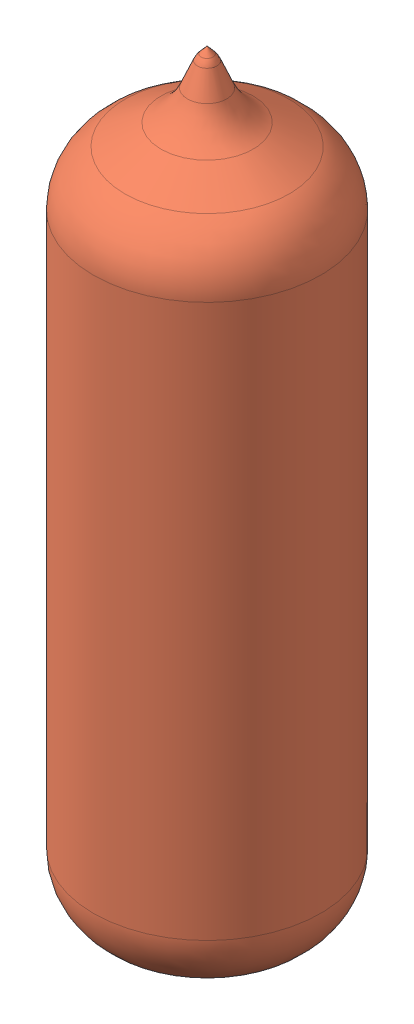
SolidWorks assembly VFD-IV11, configuration Défaut. Lengths in mm.
Overall size (10.8 36 10.8).
2 component instances, 2 part files, 1 mates.
Components (placement in the parent):
- digitsinside-1: digitsinside [Défaut] at (-3.0725 -4.5419 8.65) size (5.9 8.9 0.5)
- iv-8vfd-1: iv-8vfd [Défaut] at (-0.4335 -20.2766 8.65) size (10.8 36 10.8)
Mates (geometry in assembly coordinates):
- Coïncidente1: coincident anti-aligned: plane of digitsinside-1 through (-3.0725 -4.5419 8.65) normal (0 0 -1); plane of iv-8vfd-1 through (-0.4335 -20.2766 8.65) normal (0 0 1)
